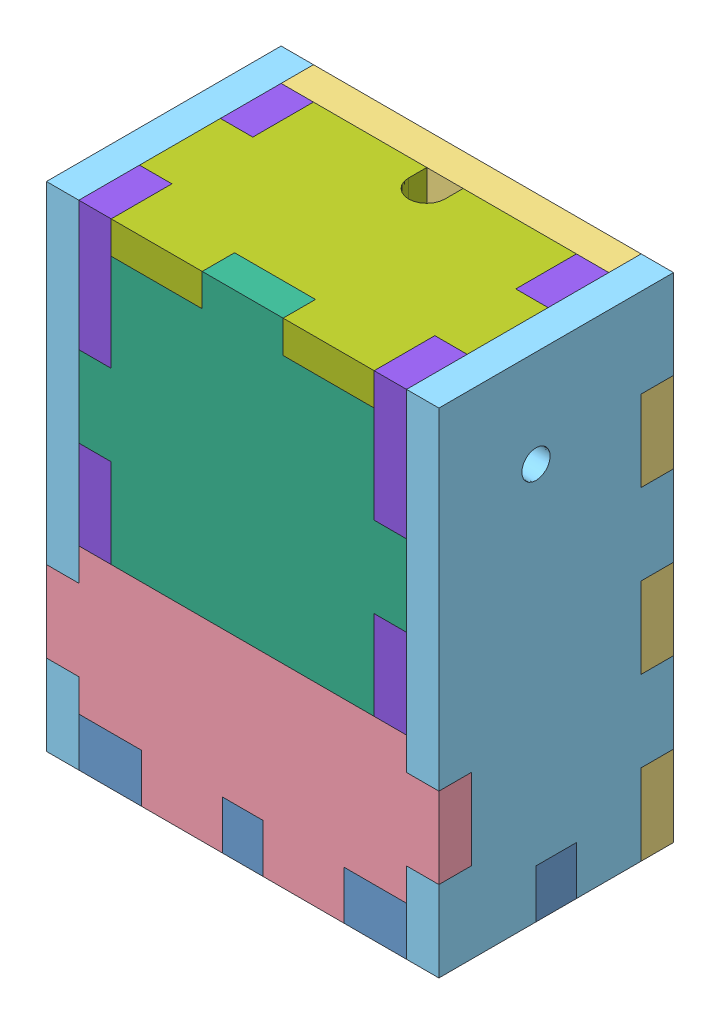
SolidWorks assembly v2_Anduri_karp, configuration Default. Lengths in mm.
Overall size (48.5 61 29).
10 component instances, 8 part files, 27 mates.
Components (placement in the parent):
- v2_andur_esi-1: v2_andur_esi [Default] at (-297.9854 64.2647 100.047) size (48.5 6 29)
- v2_andur_tof-1: v2_andur_tof [Default] at (-282.4854 67.5647 111.047) x (-1 0 0) z (0 0 -1) size (40.2 34.3 13.79)
- v2_andur_alumine-1: v2_andur_alumine [Default] at (-269.9854 126.8647 91.047) x (0 -1 0) z (-1 0 0) size (61 4 48.5)
- v2_andur_pealmine-1: v2_andur_pealmine [Default] at (-310.4854 89.8647 120.047) x (0 -1 0) z (1 0 0) size (24 4 48.5)
- v2_andur_külg-1: v2_andur_külg [Default] at (-269.9854 126.8647 95.047) x (0 -1 0) z (0 0 1) size (61 4 29)
- v2_andur_külg-2: v2_andur_külg [Default] at (-314.4854 126.8647 95.047) x (0 -1 0) z (0 0 1) size (61 4 29)
- v2_andur_kaane_lagi-1: v2_andur_kaane_lagi [Default] at (-306.4854 89.8647 120.047) x (1 0 0) z (0 1 0) size (40.5 4 37)
- v2_andur_kaane_juhtmeauk-1: v2_andur_kaane_juhtmeauk [Default] at (-306.4854 122.8647 95.047) size (40.5 4 25)
- v2_andur_kaane_külg-1: v2_andur_kaane_külg [Default] at (-310.4854 126.8647 95.047) x (0 -1 0) z (0 0 1) size (37 4 25)
- v2_andur_kaane_külg-2: v2_andur_kaane_külg [Default] at (-273.9854 126.8647 95.047) x (0 -1 0) z (0 0 1) size (37 4 25)
Mates (geometry in assembly coordinates):
- Coincident2: coincident anti-aligned: plane of v2_andur_esi-1 through (-282.4854 71.8647 100.047) normal (0 0 1); plane of andur_tof-1 through (-282.4854 69.1647 100.047) normal (0 0 -1)
- Coincident3: coincident anti-aligned: plane of v2_andur_esi-1 through (-297.9854 71.8647 100.047) normal (0 1 0); plane of andur_tof-1 through (-282.4854 71.8647 111.047) normal (0 -1 0)
- Coincident4: coincident anti-aligned: plane of v2_andur_esi-1 through (-282.4854 71.8647 102.647) normal (-1 0 0); plane of andur_tof-1 through (-282.4854 69.1647 111.047) normal (1 0 0)
- Coincident5: coincident anti-aligned: plane of v2_andur_esi-1 through (-297.9854 71.8647 100.047) normal (0 1 0); plane of v2_andur_alumine-1 through (-269.9854 71.8647 95.047) normal (0 -1 0)
- Coincident6: coincident anti-aligned: plane of v2_andur_esi-1 through (-310.4854 71.8647 95.047) normal (0 0 -1); plane of v2_andur_alumine-1 through (-269.9854 126.8647 95.047) normal (0 0 1)
- Coincident7: coincident aligned: plane of v2_andur_esi-1 through (-269.9854 71.8647 95.047) normal (1 0 0); plane of v2_andur_alumine-1 through (-269.9854 126.8647 95.047) normal (1 0 0)
- Coincident8: coincident aligned: plane of v2_andur_esi-1 through (-307.7354 65.8647 120.047) normal (0 0 1); plane of v2_andur_pealmine-1 through (-310.4854 89.8647 120.047) normal (0 0 1)
- Coincident9: coincident aligned: plane of v2_andur_alumine-1 through (-269.9854 126.8647 95.047) normal (1 0 0); plane of v2_andur_pealmine-1 through (-269.9854 89.8647 116.047) normal (1 0 0)
- Coincident10: coincident anti-aligned: plane of v2_andur_esi-1 through (-297.9854 71.8647 100.047) normal (0 1 0); plane of v2_andur_pealmine-1 through (-310.4854 71.8647 116.047) normal (0 -1 0)
- Coincident11: coincident anti-aligned: plane of v2_andur_esi-1 through (-269.9854 71.8647 95.047) normal (1 0 0); plane of v2_andur_külg-1 through (-269.9854 126.8647 95.047) normal (-1 0 0)
- Coincident12: coincident anti-aligned: plane of v2_andur_esi-1 through (-297.9854 71.8647 100.047) normal (0 1 0); plane of v2_andur_külg-1 through (-265.9854 71.8647 95.047) normal (0 -1 0)
- Coincident13: coincident anti-aligned: plane of v2_andur_pealmine-1 through (-310.4854 89.8647 116.047) normal (0 0 -1); plane of v2_andur_külg-1 through (-265.9854 126.8647 116.047) normal (0 0 1)
- Coincident14: coincident anti-aligned: plane of v2_andur_esi-1 through (-310.4854 71.8647 95.047) normal (-1 0 0); plane of v2_andur_külg-2 through (-310.4854 126.8647 95.047) normal (1 0 0)
- Coincident15: coincident aligned: plane of v2_andur_esi-1 through (-297.9854 65.8647 100.047) normal (0 -1 0); plane of v2_andur_külg-2 through (-314.4854 65.8647 95.047) normal (0 -1 0)
- Coincident16: coincident aligned: plane of v2_andur_alumine-1 through (-269.9854 126.8647 91.047) normal (0 0 -1); plane of v2_andur_külg-2 through (-314.4854 75.8647 91.047) normal (0 0 -1)
- Coincident17: coincident anti-aligned: plane of v2_andur_kaane_juhtmeauk-1 through (-306.4854 122.8647 95.047) normal (0 -1 0); plane of v2_andur_kaane_külg-1 through (-306.4854 122.8647 102.547) normal (0 1 0)
- Coincident18: coincident aligned: plane of v2_andur_kaane_juhtmeauk-1 through (-310.4854 122.8647 102.547) normal (-1 0 0); plane of v2_andur_kaane_külg-1 through (-310.4854 126.8647 95.047) normal (-1 0 0)
- Coincident19: coincident aligned: plane of v2_andur_kaane_juhtmeauk-1 through (-306.4854 126.8647 120.047) normal (0 0 1); plane of v2_andur_kaane_külg-1 through (-306.4854 126.8647 120.047) normal (0 0 1)
- Coincident20: coincident aligned: plane of v2_andur_kaane_juhtmeauk-1 through (-269.9854 122.8647 102.547) normal (1 0 0); plane of v2_andur_kaane_külg-2 through (-269.9854 126.8647 95.047) normal (1 0 0)
- Coincident21: coincident aligned: plane of v2_andur_kaane_juhtmeauk-1 through (-306.4854 126.8647 95.047) normal (0 1 0); plane of v2_andur_kaane_külg-2 through (-269.9854 126.8647 95.047) normal (0 1 0)
- Coincident22: coincident aligned: plane of v2_andur_kaane_juhtmeauk-1 through (-306.4854 126.8647 120.047) normal (0 0 1); plane of v2_andur_kaane_külg-2 through (-269.9854 126.8647 120.047) normal (0 0 1)
- Coincident23: coincident aligned: plane of v2_andur_kaane_lagi-1 through (-306.4854 89.8647 120.047) normal (0 0 1); plane of v2_andur_kaane_juhtmeauk-1 through (-306.4854 126.8647 120.047) normal (0 0 1)
- Coincident24: coincident anti-aligned: plane of v2_andur_kaane_lagi-1 through (-306.4854 122.8647 116.047) normal (0 1 0); plane of v2_andur_kaane_juhtmeauk-1 through (-306.4854 122.8647 95.047) normal (0 -1 0)
- Coincident25: coincident aligned: plane of v2_andur_kaane_lagi-1 through (-269.9854 110.8647 116.047) normal (1 0 0); plane of v2_andur_kaane_külg-2 through (-269.9854 126.8647 95.047) normal (1 0 0)
- Coincident26: coincident anti-aligned: plane of v2_andur_alumine-1 through (-269.9854 126.8647 95.047) normal (0 0 1); plane of v2_andur_kaane_juhtmeauk-1 through (-306.4854 126.8647 95.047) normal (0 0 -1)
- Coincident27: coincident anti-aligned: plane of v2_andur_külg-1 through (-269.9854 126.8647 95.047) normal (-1 0 0); plane of v2_andur_kaane_külg-2 through (-269.9854 126.8647 95.047) normal (1 0 0)
- Coincident28: coincident aligned: plane of v2_andur_alumine-1 through (-269.9854 126.8647 95.047) normal (0 1 0); plane of v2_andur_kaane_juhtmeauk-1 through (-306.4854 126.8647 95.047) normal (0 1 0)
